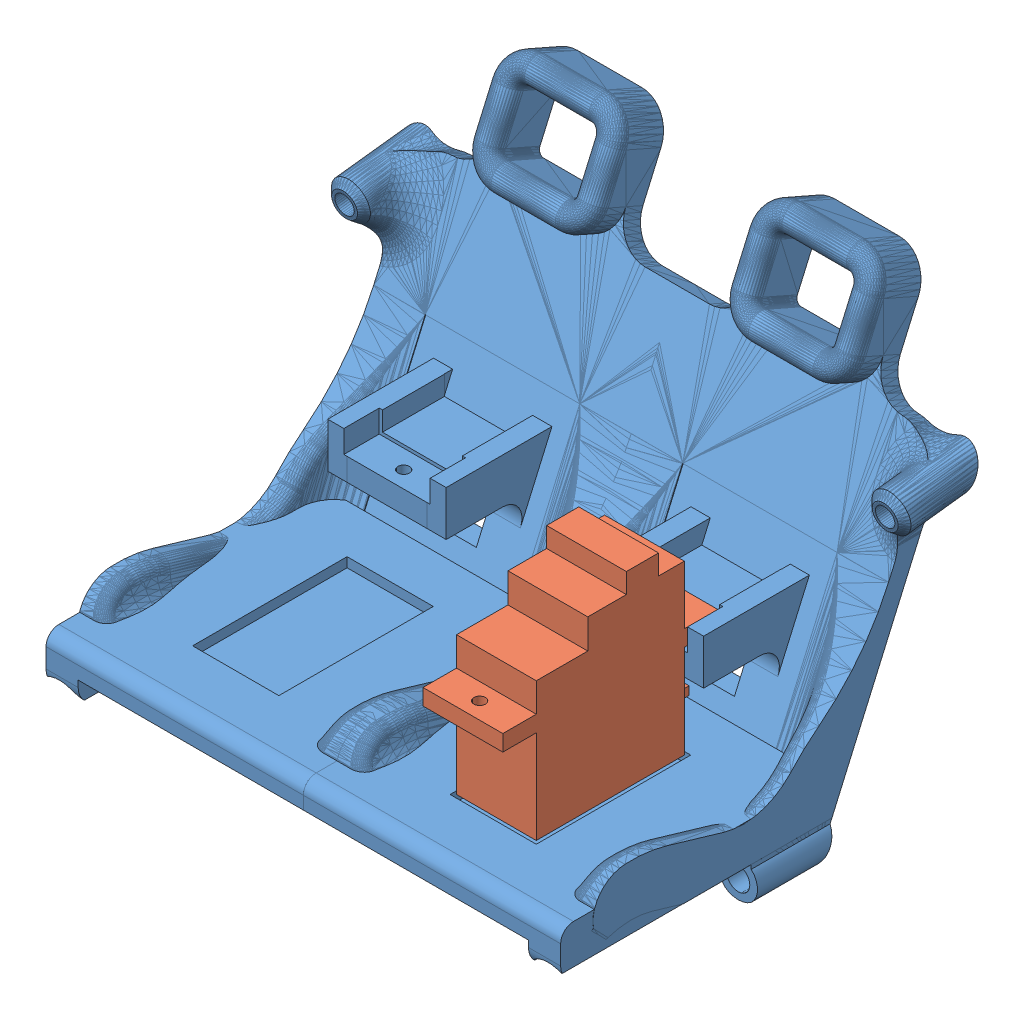
SolidWorks assembly Asientos + Servos, configuration Predeterminado. Lengths in mm.
Overall size (90 66.51 67.67).
2 component instances, 2 part files, 1 mates.
Components (placement in the parent):
- 2-1: 2 [Predeterminado] at (-12.6807 -14.5522 82.7944) size (90 66.51 67.67)
- Servo 9G-2: Servo 9G [Predeterminado] at (10.1374 4.6978 102.2944) x (0 0 -1) z (1 0 0) size (33.4 29.2 12.4)
Mates (geometry in assembly coordinates):
- Ancho1: width: plane of assembly; plane of assembly; plane of assembly; plane of assembly; plane of 2-1 through (36.3373 -14.5522 82.7944) normal (1 0 0); plane of 2-1 through (-3.6627 -14.5522 82.7944) normal (1 0 0); plane of Servo 9G-2 through (22.5374 4.6978 102.2944) normal (1 0 0); plane of Servo 9G-2 through (10.1374 4.6978 102.2944) normal (-1 0 0)
